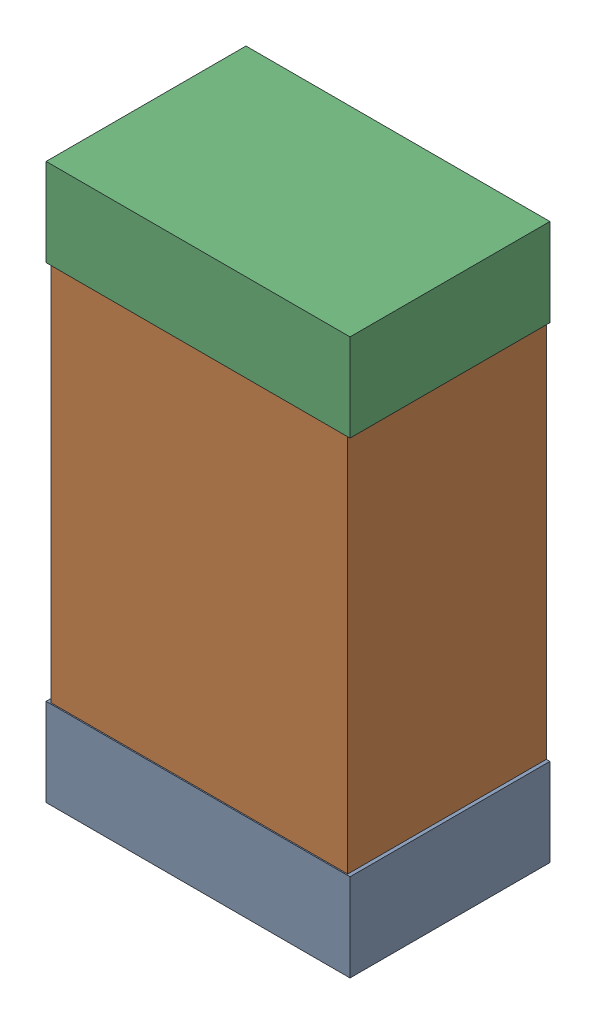
SolidWorks assembly CSSKanaloa_v2.0.0_Power, configuration Default. Lengths in mm.
Overall size (1.3 2.38 0.85).
6 component instances, 2 part files, 0 mates.
Components (placement in the parent):
- 330415056-1: 330415056 [Default] at (55.372 59.198 0) size (1.3 0.38 0.85)
  - Extruded_2-1: Extruded_2 [Default] at origin size (1.3 0.38 0.85)
- 334787376-1: 334787376 [Default] at (55.372 60.198 0) size (1.27 2.2 0.85)
  - Extruded_16-1: Extruded_16 [Default] at origin size (1.27 2.2 0.85)
- 330415056-2: 330415056 [Default] at (55.372 61.198 0) size (1.3 0.38 0.85)
  - Extruded_2-1: Extruded_2 [Default] at origin size (1.3 0.38 0.85)
